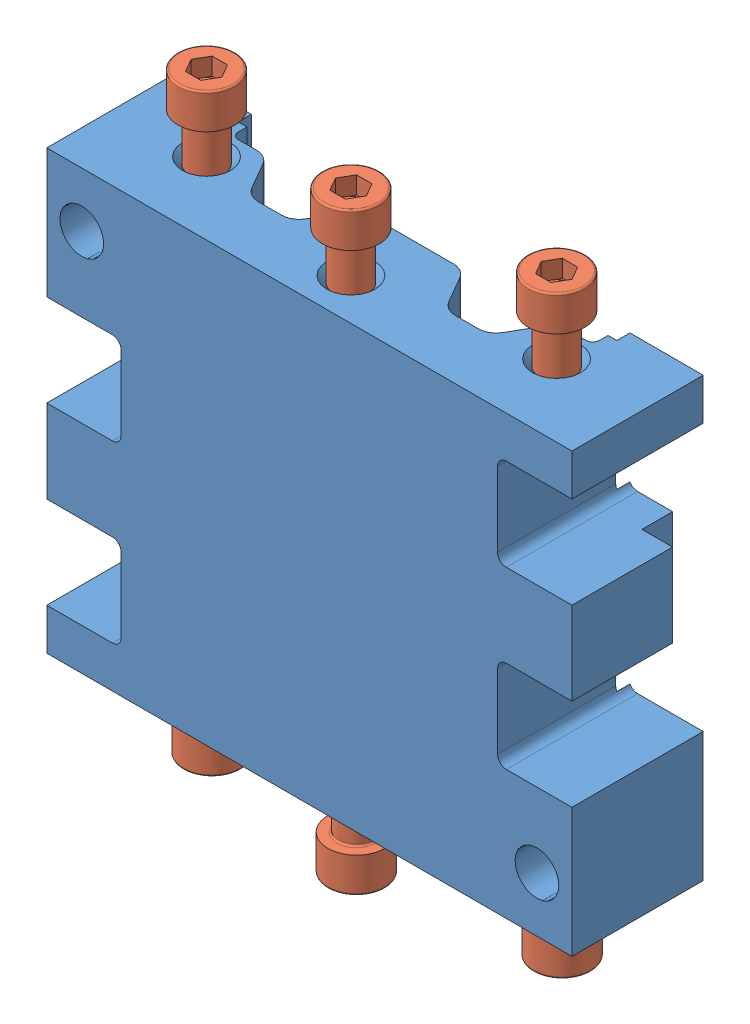
SolidWorks assembly ГТК 01.02.00 Сборка пуансона, configuration По умолчанию. Lengths in mm.
Overall size (121.25 139 30.34).
9 component instances, 3 part files, 21 mates.
Components (placement in the parent):
- ГТК 01.02.01 Пуансон-1: ГТК 01.02.01 Пуансон [По умолчанию] at origin size (120 100 30)
- ГТК 02.01.02 Боковина Пуансона-1: ГТК 02.01.02 Боковина Пуансона [По умолчанию] at (121.25 0 30) x (-1 0 0) z (0 -1 0) size (120 30.34 139)
- ГТК 02.01.02 Боковина Пуансона-2: ГТК 02.01.02 Боковина Пуансона [По умолчанию] at (0 100 30) x (1 0 0) z (0 1 0) size (120 30.34 139)
- ISO 4762 М8x16-2: ISO 4762 М8x16 [ISO 4762 M8 x 16 - 16N] at (101.25 -17.5 13.5) x (0 1 0) z (0 0 1) size (24 13 13)
- ISO 4762 М8x16-3: ISO 4762 М8x16 [ISO 4762 M8 x 16 - 16N] at (61.25 -17.5 20.5) x (0 1 0) z (0 0 1) size (24 13 13)
- ISO 4762 М8x16-4: ISO 4762 М8x16 [ISO 4762 M8 x 16 - 16N] at (21.25 -17.5 13.5) x (0 1 0) z (0 0 1) size (24 13 13)
- ISO 4762 М8x16-5: ISO 4762 М8x16 [ISO 4762 M8 x 16 - 16N] at (20 117.5 13.5) x (0 -1 0) z (0 0 1) size (24 13 13)
- ISO 4762 М8x16-6: ISO 4762 М8x16 [ISO 4762 M8 x 16 - 16N] at (60 117.5 20.5) x (0 -1 0) z (0 0 1) size (24 13 13)
- ISO 4762 М8x16-7: ISO 4762 М8x16 [ISO 4762 M8 x 16 - 16N] at (100 117.5 13.5) x (0 -1 0) z (0 0 1) size (24 13 13)
Mates (geometry in assembly coordinates):
- Совпадение1: coincident anti-aligned: plane of ГТК 01.02.01 Пуансон-1 through (0 0 30) normal (0 -1 0); plane of ГТК 02.01.02 Боковина Пуансона-1 through (121.25 0 30) normal (0 1 0)
- Концентричный1: concentric aligned: cylinder of ГТК 01.02.01 Пуансон-1 through (101.25 22 13.5) axis (0 -1 0) radius 4; cylinder of ГТК 02.01.02 Боковина Пуансона-1 through (101.25 0 13.5) axis (0 -1 0) radius 4.5
- Параллельность1: parallel aligned: cylinder of ГТК 01.02.01 Пуансон-1 through (21.25 22 13.5) axis (0 -1 0) radius 4; cylinder of ГТК 02.01.02 Боковина Пуансона-1 through (21.25 0 13.5) axis (0 -1 0) radius 4.5
- Параллельность2: parallel aligned: cylinder of ГТК 01.02.01 Пуансон-1 through (21.25 22 13.5) axis (0 -1 0) radius 4; cylinder of ГТК 02.01.02 Боковина Пуансона-1 through (21.25 0 13.5) axis (0 -1 0) radius 4.5
- Параллельность3: parallel aligned: cylinder of ГТК 01.02.01 Пуансон-1 through (21.25 22 13.5) axis (0 -1 0) radius 4; cylinder of ГТК 02.01.02 Боковина Пуансона-1 through (21.25 0 13.5) axis (0 -1 0) radius 4.5
- Концентричный9: concentric aligned: cylinder of ГТК 01.02.01 Пуансон-1 through (21.25 22 13.5) axis (0 -1 0) radius 4; cylinder of ГТК 02.01.02 Боковина Пуансона-1 through (21.25 0 13.5) axis (0 -1 0) radius 4.5
- Совпадение2: coincident anti-aligned: plane of ГТК 01.02.01 Пуансон-1 through (0 100 30) normal (0 1 0); plane of ГТК 02.01.02 Боковина Пуансона-2 through (0 100 30) normal (0 -1 0)
- Концентричный10: concentric aligned: cylinder of ГТК 01.02.01 Пуансон-1 through (20 78 13.5) axis (0 1 0) radius 4; cylinder of ГТК 02.01.02 Боковина Пуансона-2 through (20 100 13.5) axis (0 1 0) radius 4.5
- Концентричный11: concentric aligned: cylinder of ГТК 01.02.01 Пуансон-1 through (100 78 13.5) axis (0 1 0) radius 4; cylinder of ГТК 02.01.02 Боковина Пуансона-2 through (100 100 13.5) axis (0 1 0) radius 4.5
- Концентричный12: concentric aligned: cylinder of ГТК 02.01.02 Боковина Пуансона-1 through (101.25 0 13.5) axis (0 -1 0) radius 4.5; cylinder of socket head cap screw_iso-2 through (101.25 -49.25 13.5) axis (0 -1 0) radius 6.5
- Совпадение3: coincident anti-aligned: plane of ГТК 02.01.02 Боковина Пуансона-1 through (101.25 -9.5 13.5) normal (0 -1 0); plane of socket head cap screw_iso-2 through (94.75 -9.5 13.5) normal (0 1 0)
- Концентричный13: concentric aligned: cylinder of ГТК 02.01.02 Боковина Пуансона-1 through (61.25 0 20.5) axis (0 -1 0) radius 4.5; cylinder of socket head cap screw_iso-3 through (61.25 -49.25 20.5) axis (0 -1 0) radius 6.5
- Совпадение4: coincident anti-aligned: plane of ГТК 02.01.02 Боковина Пуансона-1 through (61.25 -9.5 20.5) normal (0 -1 0); plane of socket head cap screw_iso-3 through (54.75 -9.5 20.5) normal (0 1 0)
- Концентричный14: concentric aligned: cylinder of ГТК 02.01.02 Боковина Пуансона-1 through (21.25 0 13.5) axis (0 -1 0) radius 4.5; cylinder of socket head cap screw_iso-4 through (21.25 -49.25 13.5) axis (0 -1 0) radius 6.5
- Совпадение5: coincident anti-aligned: plane of ГТК 02.01.02 Боковина Пуансона-1 through (21.25 -9.5 13.5) normal (0 -1 0); plane of socket head cap screw_iso-4 through (14.75 -9.5 13.5) normal (0 1 0)
- Концентричный15: concentric aligned: cylinder of ГТК 02.01.02 Боковина Пуансона-2 through (20 109.5 13.5) axis (0 1 0) radius 7.5; cylinder of socket head cap screw_iso-5 through (20 149.25 13.5) axis (0 1 0) radius 6.5
- Совпадение6: coincident anti-aligned: plane of ГТК 02.01.02 Боковина Пуансона-2 through (20 109.5 13.5) normal (0 1 0); plane of socket head cap screw_iso-5 through (26.5 109.5 13.5) normal (0 -1 0)
- Концентричный16: concentric aligned: cylinder of ГТК 02.01.02 Боковина Пуансона-2 through (60 109.5 20.5) axis (0 1 0) radius 7.5; cylinder of socket head cap screw_iso-6 through (60 149.25 20.5) axis (0 1 0) radius 6.5
- Совпадение7: coincident anti-aligned: plane of ГТК 02.01.02 Боковина Пуансона-2 through (60 109.5 20.5) normal (0 1 0); plane of socket head cap screw_iso-6 through (66.5 109.5 20.5) normal (0 -1 0)
- Концентричный17: concentric aligned: cylinder of ГТК 02.01.02 Боковина Пуансона-2 through (100 100 13.5) axis (0 1 0) radius 4.5; cylinder of socket head cap screw_iso-7 through (100 149.25 13.5) axis (0 1 0) radius 6.5
- Совпадение8: coincident anti-aligned: plane of ГТК 02.01.02 Боковина Пуансона-2 through (100 109.5 13.5) normal (0 1 0); plane of socket head cap screw_iso-7 through (106.5 109.5 13.5) normal (0 -1 0)
